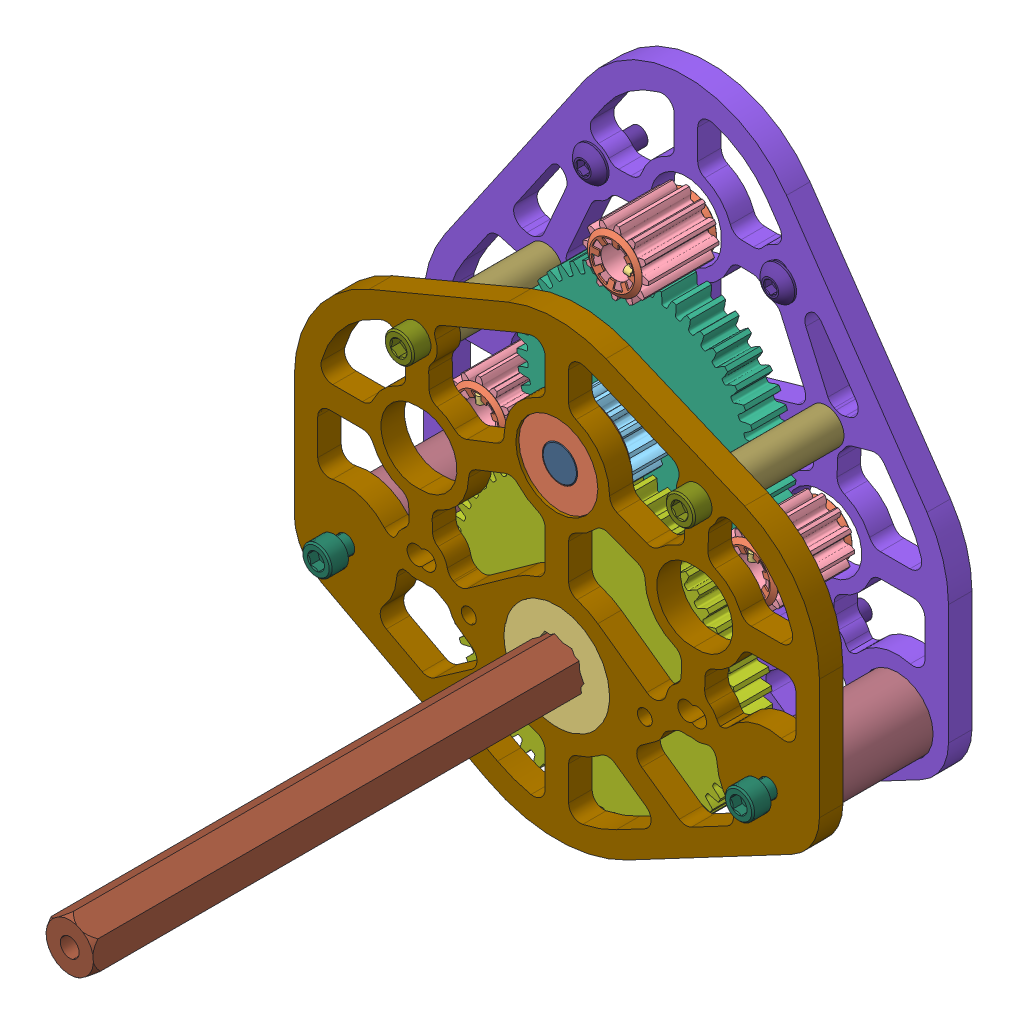
SolidWorks assembly WCP SS Gearbox VEX-217-3421, configuration Default. Lengths in mm.
Overall size (142.06 175.41 179.39).
39 component instances, 21 part files, 0 mates.
Components (placement in the parent):
- 217-2731-1: 217-2731 [Default] at (0 -47.0408 0) x (0.751182 -0.660095 0) z (-0.660095 -0.751182 0) size (31.12 7.94 31.12)
- 217-2733-1: 217-2733 [Default] at (0 0 7.9375) x (0 0 -1) z (0.979051 -0.203616 0) size (7.11 24.61 24.61)
- 217-2733-2: 217-2733 [Default] at (0 0 33.3375) x (0 0 1) z (-0.773016 -0.634387 0) size (7.11 24.61 24.61)
- 217-2734-1: 217-2734 [Default] at (0 -47.0408 41.275) x (0.443695 -0.896178 0) z (0.896178 0.443695 0) size (31.12 7.94 31.12)
- 217-2614-001_12t-1: 217-2614-001_12t [Default] at (-36.6388 -14.5464 15.7856) x (0.998588 0.053124 0) z (0 0 1) size (18.29 18.29 19)
- 217-2614-001_12t-2: 217-2614-001_12t [Default] at (36.6388 -14.5464 15.7856) x (0.998588 -0.053124 0) z (0 0 1) size (18.29 18.29 19)
- 217-2614-001_12t-3: 217-2614-001_12t [Default] at (-0.0318 39.4208 15.7856) x (-0.050001 -0.998749 0) z (0 0 1) size (18.29 18.29 19)
- 217-3100-001_14t-1: 217-3100-001_14t [Default] at (0 0 26.9367) size (20.32 20.6 12.7)
- 217-2711-002 Rev1_50t-1: 217-2711-002 Rev1_50t [Default] at (0 0 14.2621) x (0.986398 -0.164372 0) z (0 0 1) size (66.7 66.76 12.65)
- 217-2714-002 Rev1_60t-1: 217-2714-002 Rev1_60t [Default] at (0 -47.0408 27.0129) x (-0.529495 -0.848313 0) z (0 0 1) size (79.34 79.34 12.65)
- 217-3421-001 Rev1-1: 217-3421-001 Rev1 [Default] at origin size (142.02 161.39 6.35)
- 217-3421-002 Rev1-1: 217-3421-002 Rev1 [Default] at (0 0 41.275) x (-1 0 0) z (0 0 -1) size (142.06 121.97 6.35)
- 217-3421-003 Rev1-1: 217-3421-003 Rev1 [Default] at (0 0 20.6375) x (0.721889 -0.692009 0) z (0 0 1) size (11 9.53 39.69)
- 217-3421-004 Rev1-1: 217-3421-004 Rev1 [Default] at (0 -47.0408 90.4875) x (0.085938 -0.9963 0) z (0 0 1) size (15.59 12.7 175.64)
- 217-3421-005 Rev1-1: 217-3421-005 Rev1 [Default] at (-37.9881 10.8177 20.6375) size (9.53 9.53 28.57)
- 217-3421-005 Rev1-2: 217-3421-005 Rev1 [Default] at (37.9881 10.8177 20.6375) size (9.53 9.53 28.57)
- 217-3421-006 Rev1-1: 217-3421-006 Rev1 [Default] at (-57.15 -47.0408 20.6375) size (19.13 19.13 34.92)
- 217-3421-006 Rev1-2: 217-3421-006 Rev1 [Default] at (57.15 -47.0408 20.6375) x (-0.69928 -0.714848 0) z (0 0 1) size (19.13 19.13 34.92)
- 217-3261-001 Rev1-1: 217-3261-001 Rev1 [Default] at (0 -47.0408 14.2875) x (0.996376 0.085057 0) z (0 0 1) size (19.5 19.5 12.7)
- 217-3421-007 Rev1-1: 217-3421-007 Rev1 [Default] at (57.15 -47.0408 44.45) x (0 0 -1) z (0.954847 0.297099 0) size (55.85 7.92 7.92)
- 217-3421-007 Rev1-2: 217-3421-007 Rev1 [Default] at (-57.15 -47.0408 44.45) x (0 0 -1) z (0.954847 0.297099 0) size (55.85 7.92 7.92)
- 217-3421-008 Rev1-1: 217-3421-008 Rev1 [Default] at (38.0118 10.8086 41.275) x (0 0 -1) z (0.913132 -0.407664 0) size (52.68 7.92 7.92)
- 217-3421-008 Rev1-2: 217-3421-008 Rev1 [Default] at (-38.0118 10.8086 41.275) x (0 0 -1) z (0.993597 -0.112983 0) size (52.68 7.92 7.92)
- 217-3421-009 Rev1-1: 217-3421-009 Rev1 [Default] at (35.2895 -39.9105 6.35) x (0 0 -1) z (0.999615 0.027745 0) size (15.78 9.26 9.25)
- 217-3421-009 Rev1-2: 217-3421-009 Rev1 [Default] at (-25.4 40.6908 6.35) x (0 0 -1) z (0.999615 0.027745 0) size (15.78 9.26 9.25)
- 217-3421-009 Rev1-3: 217-3421-009 Rev1 [Default] at (25.3365 38.1508 6.35) x (0 0 -1) z (0.999615 0.027745 0) size (15.78 9.26 9.25)
- 217-3421-009 Rev1-4: 217-3421-009 Rev1 [Default] at (-35.2895 -39.9105 6.35) x (0 0 -1) z (0.999615 0.027745 0) size (15.78 9.26 9.25)
- 217-3421-010 Rev1-1: 217-3421-010 Rev1 [Default] at (57.15 -47.0408 0) x (-0.081132 0.996703 0) z (-0.996703 -0.081132 0) size (9.53 6.13 11)
- 217-3421-010 Rev1-2: 217-3421-010 Rev1 [Default] at (-57.15 -47.0408 0) x (0.007726 -0.99997 0) z (0.99997 0.007726 0) size (9.53 6.13 11)
- 217-3421-011 Rev2_97633A200-1: 217-3421-011 Rev2_97633A200 [Default] at (0 -47.0408 -0.4445) x (0 0 -1) z (0.696366 -0.717687 0) size (0.89 16.1 14.34)
- 217-2614-002_98430A132-1: 217-2614-002_98430A132 [Default] at (-0.0318 39.4208 26.352) x (0 0 -1) z (0.616155 -0.787625 0) size (1.2 14.83 14.83)
- 217-2614-002_98430A132-2: 217-2614-002_98430A132 [Default] at (36.6388 -14.5464 26.352) x (0 0 -1) z (0.907937 -0.419106 0) size (1.2 14.83 14.83)
- 217-2614-002_98430A132-3: 217-2614-002_98430A132 [Default] at (-36.6388 -14.5464 26.352) x (0 0 -1) z (0.939176 -0.343437 0) size (1.2 14.83 14.83)
- 217-2761-001 rev1-1: 217-2761-001 rev1 [Default] at (36.8407 -10.7518 16.1) x (0.998588 -0.053124 0) z (0 0 1) size (2 2 20)
- 217-2761-001 rev1-2: 217-2761-001 rev1 [Default] at (-36.8407 -10.7518 16.1) x (0.998588 0.053124 0) z (0 0 1) size (2 2 20)
- 217-2761-001 rev1-3: 217-2761-001 rev1 [Default] at (3.7635 39.2308 16.1) x (0.050001 0.998749 0) z (0 0 1) size (2 2 20)
- 217-2614-002_98430A132-4: 217-2614-002_98430A132 [Default] at (36.6388 -14.5464 6.286) x (0 0 -1) z (0.616155 -0.787625 0) size (1.2 14.83 14.83)
- 217-2614-002_98430A132-5: 217-2614-002_98430A132 [Default] at (-0.0318 39.4208 6.286) x (0 0 -1) z (0.40614 -0.913811 0) size (1.2 14.83 14.83)
- 217-2614-002_98430A132-6: 217-2614-002_98430A132 [Default] at (-36.6388 -14.5464 6.286) x (0 0 -1) z (0.609976 -0.79242 0) size (1.2 14.83 14.83)
